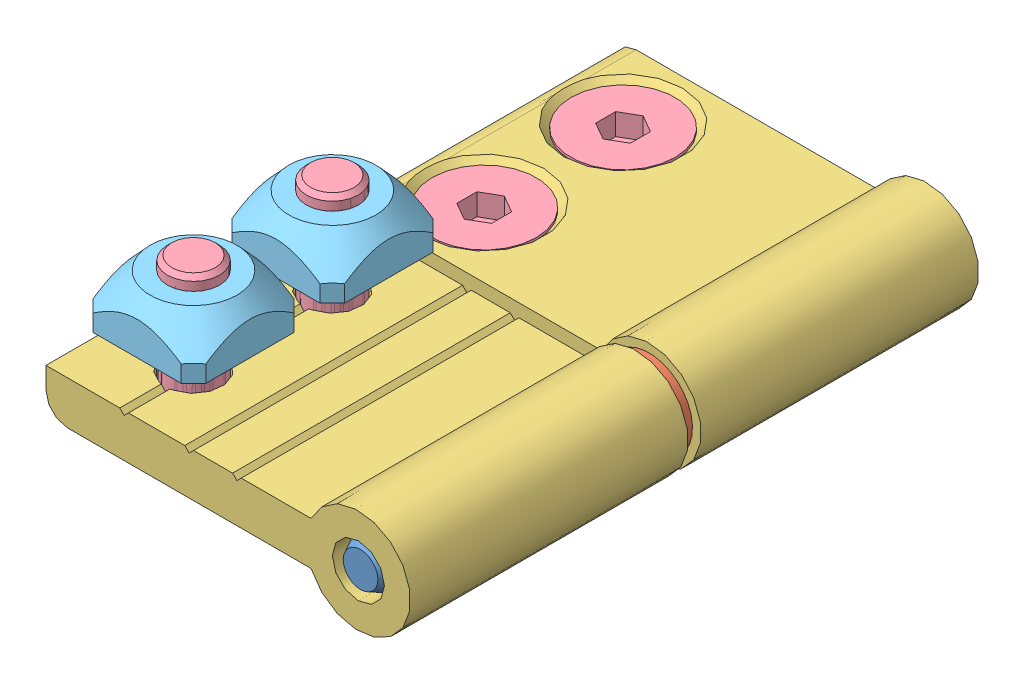
SolidWorks assembly 21.1378 HINGE L 45_45 RIGHT HAND, configuration Default. Lengths in mm.
Overall size (42.08 28 65.5).
12 component instances, 5 part files, 22 mates.
Components (placement in the parent):
- 21.1096 HINGE PIN-1: 21.1096 HINGE PIN [Default] at origin size (6.07 6.07 65)
- 21.1096 HINGE WASHER-1: 21.1096 HINGE WASHER [Default] at (0 0 31.75) x (0.969126 0.246564 0) z (0 0 1) size (10 10 1.5)
- 21.1378 HINGE L 45 AL BLOCK-1: 21.1378 HINGE L 45 AL BLOCK [Default] at (0 0 15.75) x (-1 0 0) z (0 0 -1) size (42 12 32)
- 21.1378 HINGE L 45 AL BLOCK-2: 21.1378 HINGE L 45 AL BLOCK [Default] at (0 0 49.25) x (-1 0 0) z (0 0 1) size (42 12 32)
- 21.1506 M6x16 C'SUNK-1: 21.1506 M6x16 C'SUNK [Default] at (-27 2 23.75) x (1 0 0) z (0 1 0) size (12 12 16)
- 21.1506 M6x16 C'SUNK-2: 21.1506 M6x16 C'SUNK [Default] at (-27 2 7.75) x (1 0 0) z (0 1 0) size (12 12 16)
- 21.1506 M6x16 C'SUNK-3: 21.1506 M6x16 C'SUNK [Default] at (-27 -2 57.25) x (1 0 0) z (0 -1 0) size (12 12 16)
- 21.1506 M6x16 C'SUNK-4: 21.1506 M6x16 C'SUNK [Default] at (-27 -2 41.25) x (1 0 0) z (0 -1 0) size (12 12 16)
- 21.1330 M6 SQUARE NUT-1: 21.1330 M6 SQUARE NUT [Default] at (-27 -7 23.75) x (1 0 0) z (0 1 0) size (13 13 5.5)
- 21.1330 M6 SQUARE NUT-2: 21.1330 M6 SQUARE NUT [Default] at (-27 -7 7.75) x (1 0 0) z (0 1 0) size (13 13 5.5)
- 21.1330 M6 SQUARE NUT-3: 21.1330 M6 SQUARE NUT [Default] at (-27 7 57.25) x (1 0 0) z (0 -1 0) size (13 13 5.5)
- 21.1330 M6 SQUARE NUT-4: 21.1330 M6 SQUARE NUT [Default] at (-27 7 41.25) x (1 0 0) z (0 -1 0) size (13 13 5.5)
Mates (geometry in assembly coordinates):
- Coincident1: coincident aligned: axis of 21.1096 HINGE PIN-1; axis of 21.1096 HINGE WASHER-1
- Coincident2: coincident aligned: axis of 21.1378 HINGE L 45 AL BLOCK-1; axis of 21.1096 HINGE PIN-1
- Distance1: distance = 0.25 mm aligned: plane of 21.1096 HINGE PIN-1 through (0 0 0) normal (0 0 -1); plane of 21.1378 HINGE L 45 AL BLOCK-1 through (-14.3887 -0.0537 -0.25) normal (0 0 -1)
- Coincident4: coincident anti-aligned: axis of 21.1096 HINGE PIN-1; axis of 21.1378 HINGE L 45 AL BLOCK-2
- Coincident5: coincident anti-aligned: plane of 21.1096 HINGE WASHER-1 through (0 0 31.75) normal (0 0 -1); plane of 21.1378 HINGE L 45 AL BLOCK-1 through (-14.3887 -0.0537 31.75) normal (0 0 1)
- Coincident6: coincident anti-aligned: plane of 21.1096 HINGE WASHER-1 through (0 0 33.25) normal (0 0 1); plane of 21.1378 HINGE L 45 AL BLOCK-2 through (-14.3887 0.0537 33.25) normal (0 0 -1)
- Coincident7: coincident aligned: axis of 21.1506 M6x16 C'SUNK-2; axis of 21.1378 HINGE L 45 AL BLOCK-1
- Coincident8: coincident aligned: axis of 21.1506 M6x16 C'SUNK-1; axis of 21.1378 HINGE L 45 AL BLOCK-1
- Coincident9: coincident aligned: axis of 21.1378 HINGE L 45 AL BLOCK-2; axis of 21.1506 M6x16 C'SUNK-4
- Coincident10: coincident aligned: axis of 21.1378 HINGE L 45 AL BLOCK-2; axis of 21.1506 M6x16 C'SUNK-3
- Coincident11: coincident aligned: plane of 21.1506 M6x16 C'SUNK-1 through (-24 2 23.75) normal (0 1 0); plane of 21.1506 M6x16 C'SUNK-2 through (-24 2 7.75) normal (0 1 0)
- Distance2: distance = 0.5 mm aligned: plane of 21.1506 M6x16 C'SUNK-2 through (-24 2 7.75) normal (0 1 0); plane of 21.1378 HINGE L 45 AL BLOCK-1 through (-33.5 2.5 15.75) normal (0 1 0)
- Coincident13: coincident aligned: plane of 21.1506 M6x16 C'SUNK-3 through (-24 -2 57.25) normal (0 -1 0); plane of 21.1506 M6x16 C'SUNK-4 through (-24 -2 41.25) normal (0 -1 0)
- Distance3: distance = 0.5 mm aligned: plane of 21.1506 M6x16 C'SUNK-3 through (-24 -2 57.25) normal (0 -1 0); plane of 21.1378 HINGE L 45 AL BLOCK-2 through (-33.5 -2.5 49.25) normal (0 -1 0)
- Coincident15: coincident aligned: axis of 21.1330 M6 SQUARE NUT-3; axis of 21.1506 M6x16 C'SUNK-3
- Coincident16: coincident aligned: axis of 21.1506 M6x16 C'SUNK-4; axis of 21.1330 M6 SQUARE NUT-4
- Coincident17: coincident aligned: plane of 21.1330 M6 SQUARE NUT-3 through (-27 7 57.25) normal (0 -1 0); plane of 21.1330 M6 SQUARE NUT-4 through (-27 7 41.25) normal (0 -1 0)
- Distance4: distance = 4.5 mm anti-aligned: plane of 21.1330 M6 SQUARE NUT-4 through (-27 7 41.25) normal (0 -1 0); plane of 21.1378 HINGE L 45 AL BLOCK-2 through (-27.5 2.5 49.25) normal (0 1 0)
- Coincident19: coincident aligned: axis of 21.1330 M6 SQUARE NUT-2; axis of 21.1506 M6x16 C'SUNK-2
- Coincident20: coincident aligned: axis of 21.1506 M6x16 C'SUNK-1; axis of ?
- Distance5: distance = 4.5 mm anti-aligned: plane of 21.1330 M6 SQUARE NUT-2 through (-27 -7 7.75) normal (0 1 0); plane of 21.1378 HINGE L 45 AL BLOCK-1 through (-27.5 -2.5 15.75) normal (0 -1 0)
- Coincident22: coincident aligned: plane of ? through (-27 30.5423 23.75) normal (0 1 0); plane of 21.1330 M6 SQUARE NUT-2 through (-27 -7 7.75) normal (0 1 0)
